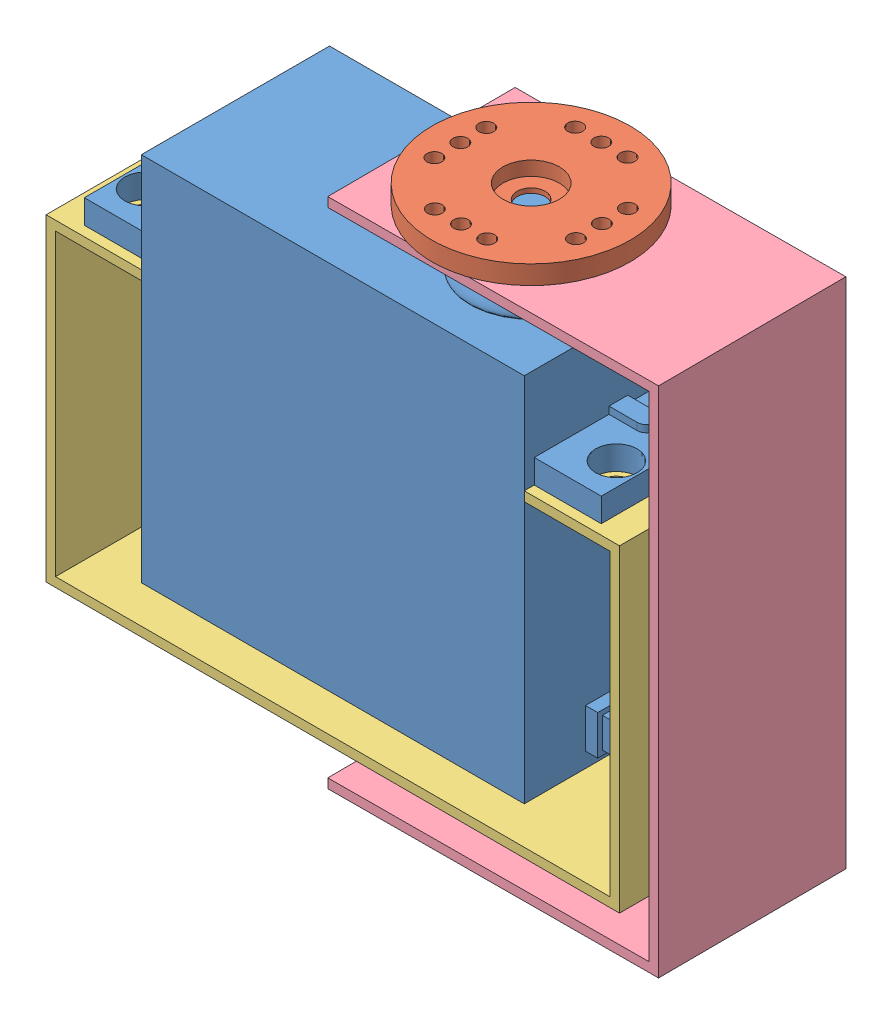
SolidWorks assembly servo_motor_bracket, configuration ﾃﾞﾌｫﾙﾄ. Lengths in mm.
Overall size (64.98 56.5 21.14).
5 component instances, 5 part files, 7 mates.
Components (placement in the parent):
- servo_motor-1: servo_motor [ﾃﾞﾌｫﾙﾄ] at (-18.1762 -22.7875 64.94) size (54.94 45.5 20)
- servo_motor_soucer-1: servo_motor_soucer [ﾃﾞﾌｫﾙﾄ] at (13.2538 22.7125 54.94) x (0.99999 0 -0.004476) z (0.004476 0 0.99999) size (21.05 5.7 21.05)
- servo_bracket1_base-2: servo_bracket1_base [ﾃﾞﾌｫﾙﾄ] at (-28.2962 -27.7875 64.94) size (60.94 33.81 20)
- servo_bracket1_cover-1: servo_bracket1_cover [ﾃﾞﾌｫﾙﾄ] at (35.6884 -31.7875 64.8397) x (0.99999 0 -0.004476) z (0.004476 0 0.99999) size (35 54.5 20)
- M3_spacer-1: M3_spacer [ﾃﾞﾌｫﾙﾄ] at (13.2538 -30.7875 54.94) size (7 3 7)
Mates (geometry in assembly coordinates):
- 一致3: coincident anti-aligned: circle of servo_motor-1; circle of servo_motor_soucer-1
- 同心円3: concentric aligned: circle of servo_motor-1; circle of servo_bracket1_base-2
- 一致4: coincident anti-aligned: plane of servo_motor-1 through (29.6438 6.0225 63.88) normal (0 -1 0); plane of servo_bracket1_base-2 through (-28.2962 6.0225 64.94) normal (0 1 0)
- 同心円4: concentric aligned: circle of servo_motor_soucer-1; circle of servo_bracket1_cover-1
- 同心円5: concentric aligned: circle of servo_motor_soucer-1; circle of servo_bracket1_cover-1
- 一致6: coincident anti-aligned: plane of servo_motor_soucer-1 through (13.2538 22.7125 54.94) normal (0 -1 0); plane of servo_bracket1_cover-1 through (36.6884 22.7125 64.8352) normal (0 1 0)
- 一致7: coincident anti-aligned: circle of servo_bracket1_base-2; circle of M3_spacer-1
